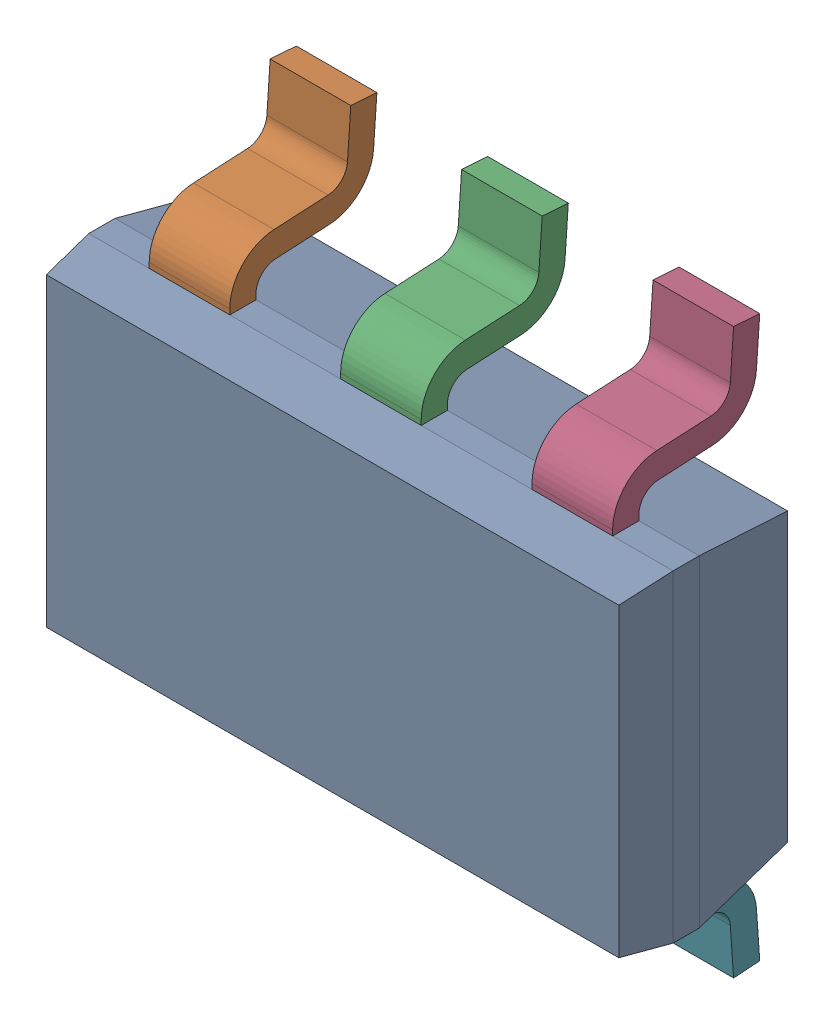
SolidWorks assembly U5, configuration ﾃﾞﾌｫﾙﾄ. Lengths in mm.
Overall size (2.9 2.8 0.97).
8 component instances, 2 part files, 0 mates.
Components (placement in the parent):
- DDC0006A-1: DDC0006A [ﾃﾞﾌｫﾙﾄ] at (45.085 15.875 0) x (0 1 0) z (0 0 1) size (2.8 2.9 0.97)
  - BODY-SOT-1: BODY-SOT [ﾃﾞﾌｫﾙﾄ] at (0 0 0.73) x (0 1 0) z (1 0 0) size (2.9 0.87 1.6)
  - LEAD-SOT-1: LEAD-SOT [ﾃﾞﾌｫﾙﾄ] at (0.9409 0.95 0.25) x (0 1 0) z (1 0 0) size (0.4 0.73 0.6)
  - LEAD-SOT-2: LEAD-SOT [ﾃﾞﾌｫﾙﾄ] at (0.9409 0 0.25) x (0 1 0) z (1 0 0) size (0.4 0.73 0.6)
  - LEAD-SOT-3: LEAD-SOT [ﾃﾞﾌｫﾙﾄ] at (0.9409 -0.95 0.25) x (0 1 0) z (1 0 0) size (0.4 0.73 0.6)
  - LEAD-SOT-4: LEAD-SOT [ﾃﾞﾌｫﾙﾄ] at (-0.9409 0.95 0.25) x (0 -1 0) z (-1 0 0) size (0.4 0.73 0.6)
  - LEAD-SOT-5: LEAD-SOT [ﾃﾞﾌｫﾙﾄ] at (-0.9409 0 0.25) x (0 -1 0) z (-1 0 0) size (0.4 0.73 0.6)
  - LEAD-SOT-6: LEAD-SOT [ﾃﾞﾌｫﾙﾄ] at (-0.9409 -0.95 0.25) x (0 -1 0) z (-1 0 0) size (0.4 0.73 0.6)
